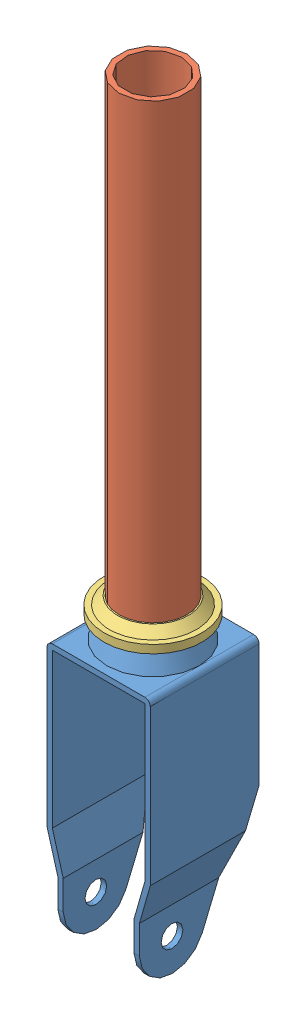
SolidWorks assembly support roue, configuration Défaut. Lengths in mm.
Overall size (38 275 40).
3 component instances, 3 part files, 8 mates.
Components (placement in the parent):
- fourche-1: fourche [Défaut] at origin size (38 103 40)
- tube pivot-1: tube pivot [Défaut] at origin size (25 180 25)
- bague arrêt-1: bague arrêt [Default] at origin size (36 6 36)
Mates (geometry in assembly coordinates):
- Sur place1: in place: plane of ?; moOrthogonalPlaneRef_w of ? through (-1000 0 0) axis (0 0 1); line of ? through (1000 -1000 0) axis (0 0 1); unknown of ?
- Coïncidente1: coincident aligned: plane of tube pivot-1; plane of assembly
- Coïncidente2: coincident aligned: plane of ? through (0 0 0) normal (0 1 0)
- Coïncidente3: coincident anti-aligned: plane of ? through (0 0 0) normal (1 0 0)
- Sur place3: in place: line of ? through (0 0 0) axis (0 0 1); line of ? through (-1000 0 0) axis (0 0 1); line of ? through (1000 -1000 0) axis (0 0 1); unknown of ?
- Coïncidente10: coincident aligned: plane of bague arrêt-1; plane of assembly
- Coïncidente11: coincident aligned: plane of ? through (0 0 0) normal (0 1 0)
- Coïncidente12: coincident anti-aligned: plane of ? through (0 0 0) normal (1 0 0)
